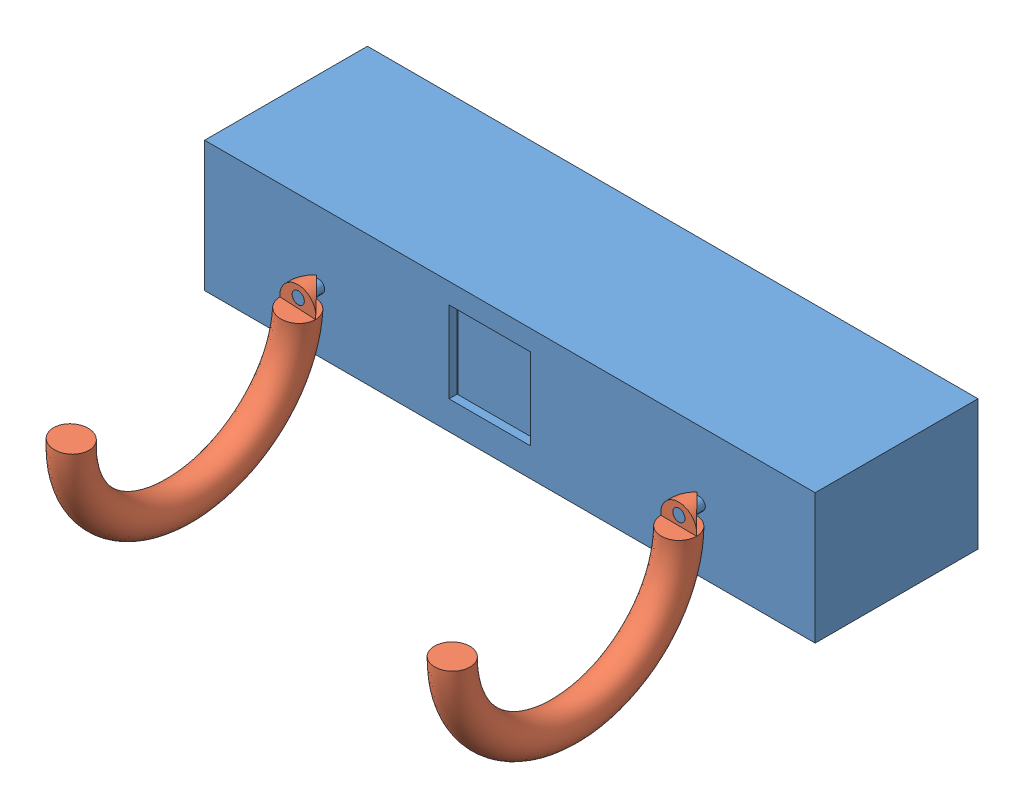
SolidWorks assembly Nishta, configuration Default. Lengths in mm.
Overall size (150 66.42 112.15).
3 component instances, 2 part files, 6 mates.
Components (placement in the parent):
- solidworksbox-1: solidworksbox [Default] at (50.7544 93.9697 115.6107) x (1 0 0) z (0 0 -1) size (150 32 45)
- solidworkshook-1: solidworkshook [Default] at (2.4891 52.5307 175.2786) x (-0.017154 -0.331042 -0.94346) z (0.99866 -0.051748 0) size (62.57 47.64 8.75)
- solidworkshook-2: solidworkshook [Default] at (96.9938 53.016 175.2786) x (-0.003671 -0.331466 -0.94346) z (0.999939 -0.011074 0) size (62.57 47.64 8.75)
Mates (geometry in assembly coordinates):
- Concentric1: concentric: cylinder of solidworksbox-1 through (3.7544 76.9488 140.6107) axis (0 0 -1) radius 1.5; cylinder of solidworkshook-1 through (3.7544 76.9488 130.6107) axis (0 0 1) radius 1.5
- Coincident1: coincident: plane of solidworksbox-1 through (3.7544 76.9488 140.6107) normal (0 0 1); plane of solidworkshook-1 through (-0.2155 84.8807 140.6107) normal (0 0 1)
- Lock1: lock: unknown of solidworksbox-1; unknown of solidworkshook-1
- Concentric2: concentric: cylinder of solidworksbox-1 through (97.2646 77.4654 140.6107) axis (0 0 -1) radius 1.5; cylinder of solidworkshook-2 through (97.2646 77.4654 130.6107) axis (0 0 1) radius 1.5
- Coincident3: coincident: plane of solidworksbox-1 through (97.2646 77.4654 140.6107) normal (0 0 1); plane of solidworkshook-2 through (92.9753 85.2292 140.6107) normal (0 0 1)
- Lock2: lock: unknown of solidworksbox-1; unknown of solidworkshook-2
